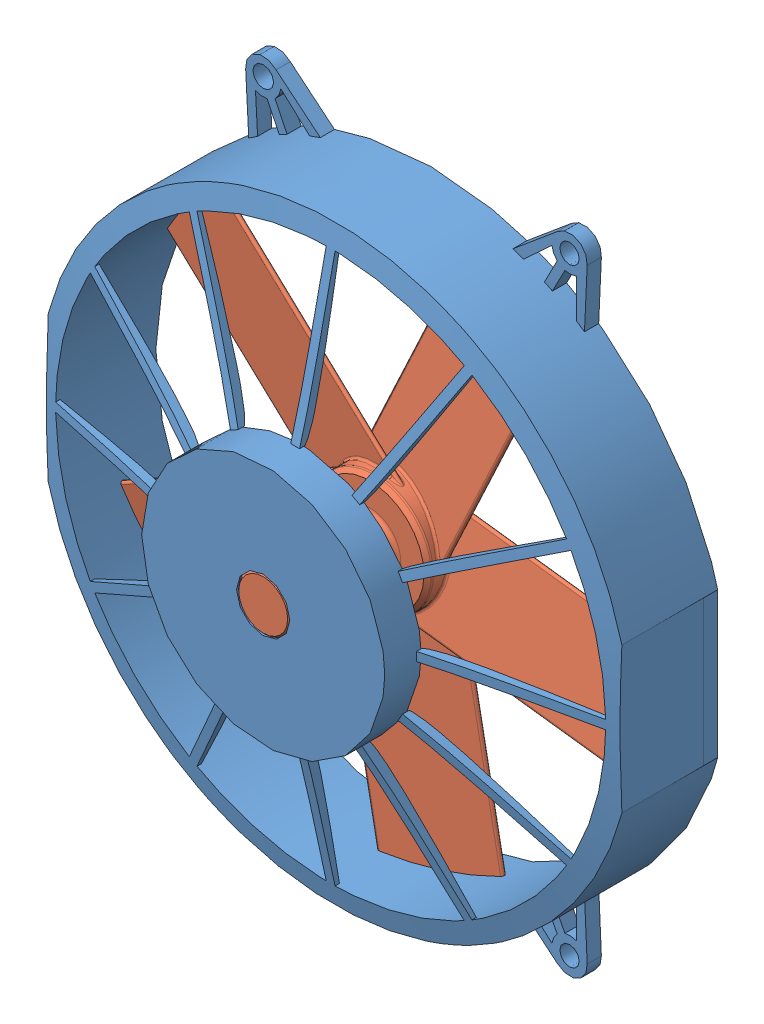
SolidWorks assembly Heat Exchange Fan, configuration Default. Lengths in mm.
Overall size (335.38 339.32 78.7).
2 component instances, 2 part files, 2 mates.
Components (placement in the parent):
- thing-1: thing [Default] at (-188.5814 -196.1052 232.7428) size (277.96 302.16 78.7)
- Fan Blade-1: Fan Blade [Default] at (128.693 199.7044 319.0764) x (0.48404 -0.875046 0) z (0 0 -1) size (253.26 243.18 60)
Mates (geometry in assembly coordinates):
- Concentric1: concentric anti-aligned: cylinder of thing-1 through (128.693 199.7044 319.0764) axis (0 0 -1) radius 129.0855; cylinder of Fan Blade-1 through (128.693 199.7044 289.0764) axis (0 0 1) radius 12.5
- Coincident1: coincident aligned: plane of thing-1 through (128.693 199.7044 319.0764) normal (0 0 1); plane of Fan Blade-1 through (128.693 199.7044 319.0764) normal (0 0 1)
